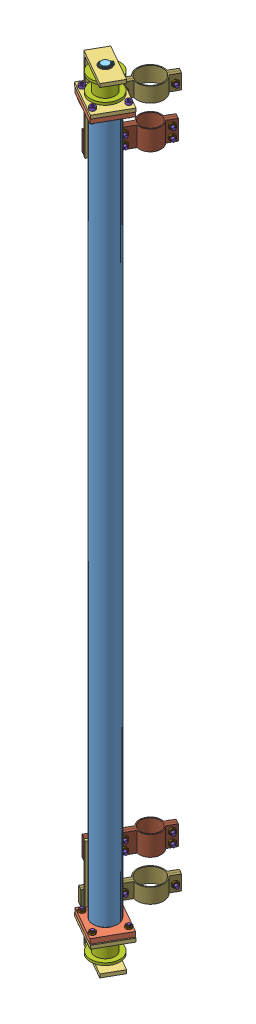
SolidWorks assembly 卷帘, configuration 默认. Lengths in mm.
Overall size (66.16 789.6 98.69).
107 component instances, 12 part files, 60 mates.
Components (placement in the parent):
- 平面涡卷弹簧内接侧-1: 平面涡卷弹簧内接侧 [默认] at (19.2815 -303.5885 0) size (25 712 25)
- 平面涡卷弹簧外接侧-1: 平面涡卷弹簧外接侧 [默认] at (23.7829 -661.5885 16.3627) x (0.49422 0 -0.869337) z (0.869337 0 0.49422) size (34 25 40)
- 平面涡卷弹簧外接侧-3: 平面涡卷弹簧外接侧 [默认] at (35.6442 54.4115 -4.5014) x (-0.49422 0 0.869337) z (0.869337 0 0.49422) size (34 25 40)
- 卷帘滑轮-安装-1: 卷帘滑轮-安装 [默认] at (13.2947 -733.0182 10.0249) x (0 1 0) z (-0.869337 0 -0.49422) size (94.8 34 43)
  - 卷帘安装架-1: 卷帘安装架 [默认] at (119.4297 11.8196 18.5) size (93 34 43)
  - deep groove ball bearings gb-1: deep groove ball bearings gb [Rolling bearings 617-8 GB 276-94] at (37.6797 11.6738 0) size (2.5 12 12)
  - deep groove ball bearings gb-2: deep groove ball bearings gb [Rolling bearings 617-8 GB 276-94] at (65.1797 11.6738 0) size (2.5 12 12)
  - 滑轮轴-1: 滑轮轴 [默认] at (51.4297 11.6738 0) x (0 0 1) z (-1 0 0) size (9.5 9.5 33.6)
  - circlips for shaft--type a small gb-2: circlips for shaft--type a small gb [GB_CONNECTING_PIECE_RING_RRA 8] at (66.4297 12.0038 0) x (0 0 1) z (-1 0 0) size (9.38 11.87 0.8)
  - circlips for shaft--type a small gb-3: circlips for shaft--type a small gb [GB_CONNECTING_PIECE_RING_RRA 8] at (36.4297 12.0038 0) x (0 0 -1) z (1 0 0) size (9.38 11.87 0.8)
  - 滑轮 - 卷帘-1: 滑轮 - 卷帘 [默认] at (41.4297 11.6738 0) x (0 -1 0) z (0 0 1) size (30 20 30)
- hexagon socket head cap screws gb-2: hexagon socket head cap screws gb [GB_FASTENER_SCREWS_HSHCS M3X12-N] at (38.3415 -673.0885 -4.6934) x (0 1 0) z (0 0 1) size (15 5.5 5.5)
- hexagon socket head cap screws gb-3: hexagon socket head cap screws gb [GB_FASTENER_SCREWS_HSHCS M3X12-N] at (13.5654 -673.0885 -18.7787) x (0 1 0) z (0 0 1) size (15 5.5 5.5)
- hexagon socket head cap screws gb-4: hexagon socket head cap screws gb [GB_FASTENER_SCREWS_HSHCS M3X12-N] at (0.2215 -673.0885 4.6934) x (0 1 0) z (0 0 1) size (15 5.5 5.5)
- hexagon socket head cap screws gb-5: hexagon socket head cap screws gb [GB_FASTENER_SCREWS_HSHCS M3X12-N] at (24.9976 -673.0885 18.7787) x (0 1 0) z (0 0 1) size (15 5.5 5.5)
- hex nuts, style 1-grades ab gb-2: hex nuts, style 1-grades ab gb [GB_FASTENER_NUT_SNAB1 M3-N] at (24.9976 -659.1885 18.7787) x (1 0 0) z (0 1 0) size (6.35 5.5 2.4)
- hex nuts, style 1-grades ab gb-3: hex nuts, style 1-grades ab gb [GB_FASTENER_NUT_SNAB1 M3-N] at (0.2215 -659.1885 4.6934) x (1 0 0) z (0 1 0) size (6.35 5.5 2.4)
- hex nuts, style 1-grades ab gb-4: hex nuts, style 1-grades ab gb [GB_FASTENER_NUT_SNAB1 M3-N] at (13.5654 -659.1885 -18.7787) x (1 0 0) z (0 1 0) size (6.35 5.5 2.4)
- hex nuts, style 1-grades ab gb-5: hex nuts, style 1-grades ab gb [GB_FASTENER_NUT_SNAB1 M3-N] at (38.3415 -659.1885 -4.6934) x (1 0 0) z (0 1 0) size (6.35 5.5 2.4)
- plain washers-n series-grade a gb-2: plain washers-n series-grade a gb [GB_FASTENER_WASHER_PWNA 3] at (-2.8064 -655.5885 -18.3081) x (-0.49422 0 0.869337) z (-0.869337 0 -0.49422) size (7 7 0.5)
- plain washers-n series-grade a gb-3: plain washers-n series-grade a gb [GB_FASTENER_WASHER_PWNA 3] at (-7.7485 -655.5885 -9.6148) x (-0.49422 0 0.869337) z (-0.869337 0 -0.49422) size (7 7 0.5)
- plain washers-n series-grade a gb-4: plain washers-n series-grade a gb [GB_FASTENER_WASHER_PWNA 3] at (-5.2773 -618.5885 -13.9617) x (-0.49422 0 0.869337) z (-0.869337 0 -0.49422) size (7 7 0.5)
- plain washers-n series-grade a gb-5: plain washers-n series-grade a gb [GB_FASTENER_WASHER_PWNA 3] at (-5.2773 -608.5885 -13.9617) x (-0.49422 0 0.869337) z (-0.869337 0 -0.49422) size (7 7 0.5)
- hexagon socket head cap screws gb-19: hexagon socket head cap screws gb [GB_FASTENER_SCREWS_HSHCS M3X16-N] at (-5.4144 -655.5885 -19.7908) x (0.869337 0 0.49422) z (-0.49422 0 0.869337) size (19 5.5 5.5)
- hexagon socket head cap screws gb-20: hexagon socket head cap screws gb [GB_FASTENER_SCREWS_HSHCS M3X16-N] at (-10.3566 -655.5885 -11.0974) x (0.869337 0 0.49422) z (-0.49422 0 0.869337) size (19 5.5 5.5)
- hexagon socket head cap screws gb-21: hexagon socket head cap screws gb [GB_FASTENER_SCREWS_HSHCS M3X16-N] at (-7.8853 -618.5885 -15.4444) x (0.869337 0 0.49422) z (-0.49422 0 0.869337) size (19 5.5 5.5)
- hexagon socket head cap screws gb-22: hexagon socket head cap screws gb [GB_FASTENER_SCREWS_HSHCS M3X16-N] at (-7.8853 -608.5885 -15.4444) x (0.869337 0 0.49422) z (-0.49422 0 0.869337) size (19 5.5 5.5)
- hex nuts, style 1-grades ab gb-19: hex nuts, style 1-grades ab gb [GB_FASTENER_NUT_SNAB1 M3-N] at (2.5966 -655.5885 -3.7335) x (0.49422 0 -0.869337) z (0.869337 0 0.49422) size (6.35 5.5 2.4)
- hex nuts, style 1-grades ab gb-20: hex nuts, style 1-grades ab gb [GB_FASTENER_NUT_SNAB1 M3-N] at (7.5388 -655.5885 -12.4269) x (0.49422 0 -0.869337) z (0.869337 0 0.49422) size (6.35 5.5 2.4)
- hex nuts, style 1-grades ab gb-21: hex nuts, style 1-grades ab gb [GB_FASTENER_NUT_SNAB1 M3-N] at (5.0678 -618.5885 -8.0805) x (0.49422 0 -0.869337) z (0.869337 0 0.49422) size (6.35 5.5 2.4)
- hex nuts, style 1-grades ab gb-22: hex nuts, style 1-grades ab gb [GB_FASTENER_NUT_SNAB1 M3-N] at (5.0678 -608.5885 -8.0805) x (0.49422 0 -0.869337) z (0.869337 0 0.49422) size (6.35 5.5 2.4)
- 卷帘滑轮-安装-4: 卷帘滑轮-安装 [默认] at (24.8336 125.8412 -10.272) x (0 -1 0) z (-0.869337 0 -0.49422) size (94.8 34 43)
  - 卷帘安装架-1: 卷帘安装架 [默认] at (119.4297 11.8196 18.5) size (93 34 43)
  - deep groove ball bearings gb-1: deep groove ball bearings gb [Rolling bearings 617-8 GB 276-94] at (37.6797 11.6738 0) size (2.5 12 12)
  - deep groove ball bearings gb-2: deep groove ball bearings gb [Rolling bearings 617-8 GB 276-94] at (65.1797 11.6738 0) size (2.5 12 12)
  - 滑轮轴-1: 滑轮轴 [默认] at (51.4297 11.6738 0) x (0 0 1) z (-1 0 0) size (9.5 9.5 33.6)
  - circlips for shaft--type a small gb-2: circlips for shaft--type a small gb [GB_CONNECTING_PIECE_RING_RRA 8] at (66.4297 12.0038 0) x (0 0 1) z (-1 0 0) size (9.38 11.87 0.8)
  - circlips for shaft--type a small gb-3: circlips for shaft--type a small gb [GB_CONNECTING_PIECE_RING_RRA 8] at (36.4297 12.0038 0) x (0 0 -1) z (1 0 0) size (9.38 11.87 0.8)
  - 滑轮 - 卷帘-1: 滑轮 - 卷帘 [默认] at (41.4297 11.6738 0) x (0 -1 0) z (0 0 1) size (30 20 30)
- hexagon socket head cap screws gb-14: hexagon socket head cap screws gb [GB_FASTENER_SCREWS_HSHCS M3X12-N] at (38.3415 65.9115 -4.6934) x (0 -1 0) z (0 0 -1) size (15 5.5 5.5)
- hexagon socket head cap screws gb-15: hexagon socket head cap screws gb [GB_FASTENER_SCREWS_HSHCS M3X12-N] at (13.5654 65.9115 -18.7787) x (0 -1 0) z (0 0 -1) size (15 5.5 5.5)
- hexagon socket head cap screws gb-16: hexagon socket head cap screws gb [GB_FASTENER_SCREWS_HSHCS M3X12-N] at (0.2215 65.9115 4.6934) x (0 -1 0) z (0 0 -1) size (15 5.5 5.5)
- hexagon socket head cap screws gb-17: hexagon socket head cap screws gb [GB_FASTENER_SCREWS_HSHCS M3X12-N] at (24.9976 65.9115 18.7787) x (0 -1 0) z (0 0 -1) size (15 5.5 5.5)
- hex nuts, style 1-grades ab gb-14: hex nuts, style 1-grades ab gb [GB_FASTENER_NUT_SNAB1 M3-N] at (24.9976 54.4115 18.7787) x (1 0 0) z (0 1 0) size (6.35 5.5 2.4)
- hex nuts, style 1-grades ab gb-15: hex nuts, style 1-grades ab gb [GB_FASTENER_NUT_SNAB1 M3-N] at (0.2215 54.4115 4.6934) x (1 0 0) z (0 1 0) size (6.35 5.5 2.4)
- hex nuts, style 1-grades ab gb-16: hex nuts, style 1-grades ab gb [GB_FASTENER_NUT_SNAB1 M3-N] at (13.5654 54.4115 -18.7787) x (1 0 0) z (0 1 0) size (6.35 5.5 2.4)
- hex nuts, style 1-grades ab gb-17: hex nuts, style 1-grades ab gb [GB_FASTENER_NUT_SNAB1 M3-N] at (38.3415 54.4115 -4.6934) x (1 0 0) z (0 1 0) size (6.35 5.5 2.4)
- 小管夹具-1: 小管夹具 [默认] at (50.6589 6.4115 7.2587) x (-0.869337 0 -0.49422) z (0 -1 0) size (22 70 20)
  - 夹具-1: 夹具 [默认] at (55.615 31.0944 -10) size (11 70 20)
  - 夹具-2: 夹具 [默认] at (55.615 31.0944 10) x (-1 0 0) z (0 0 -1) size (11 70 20)
  - plain washers-n series-grade a gb-2: plain washers-n series-grade a gb [GB_FASTENER_WASHER_PWNA 3] at (59.115 46.3859 5) x (0 0 -1) z (1 0 0) size (7 7 0.5)
  - plain washers-n series-grade a gb-3: plain washers-n series-grade a gb [GB_FASTENER_WASHER_PWNA 3] at (59.115 46.3859 -5) x (0 0 -1) z (1 0 0) size (7 7 0.5)
  - plain washers-n series-grade a gb-4: plain washers-n series-grade a gb [GB_FASTENER_WASHER_PWNA 3] at (59.115 10.8029 -5) x (0 0 -1) z (1 0 0) size (7 7 0.5)
  - plain washers-n series-grade a gb-5: plain washers-n series-grade a gb [GB_FASTENER_WASHER_PWNA 3] at (59.115 10.8029 5) x (0 0 -1) z (1 0 0) size (7 7 0.5)
  - hexagon socket head cap screws gb-2: hexagon socket head cap screws gb [GB_FASTENER_SCREWS_HSHCS M3X12-N] at (62.115 10.8029 -5) x (-1 0 0) z (0 0.924225 0.381849) size (15 5.5 5.5)
  - hexagon socket head cap screws gb-3: hexagon socket head cap screws gb [GB_FASTENER_SCREWS_HSHCS M3X12-N] at (62.115 10.8029 5) x (-1 0 0) z (0 0.924225 0.381849) size (15 5.5 5.5)
  - hexagon socket head cap screws gb-4: hexagon socket head cap screws gb [GB_FASTENER_SCREWS_HSHCS M3X12-N] at (62.115 46.3859 -5) x (-1 0 0) z (0 0.924225 0.381849) size (15 5.5 5.5)
  - hexagon socket head cap screws gb-5: hexagon socket head cap screws gb [GB_FASTENER_SCREWS_HSHCS M3X12-N] at (62.115 46.3859 5) x (-1 0 0) z (0 0.924225 0.381849) size (15 5.5 5.5)
  - hex nuts, style 1-grades ab gb-2: hex nuts, style 1-grades ab gb [GB_FASTENER_NUT_SNAB1 M3-N] at (50.215 10.8029 -5) x (0 0 1) z (-1 0 0) size (6.35 5.5 2.4)
  - hex nuts, style 1-grades ab gb-3: hex nuts, style 1-grades ab gb [GB_FASTENER_NUT_SNAB1 M3-N] at (50.215 10.8029 5) x (0 0 1) z (-1 0 0) size (6.35 5.5 2.4)
  - hex nuts, style 1-grades ab gb-4: hex nuts, style 1-grades ab gb [GB_FASTENER_NUT_SNAB1 M3-N] at (50.215 46.3859 -5) x (0 0 1) z (-1 0 0) size (6.35 5.5 2.4)
  - hex nuts, style 1-grades ab gb-5: hex nuts, style 1-grades ab gb [GB_FASTENER_NUT_SNAB1 M3-N] at (50.215 46.3859 5) x (0 0 1) z (-1 0 0) size (6.35 5.5 2.4)
- 小管夹具-2: 小管夹具 [默认] at (50.6589 -613.5885 7.2587) x (-0.869337 0 -0.49422) z (0 -1 0) size (22 70 20)
  - 夹具-1: 夹具 [默认] at (55.615 31.0944 -10) size (11 70 20)
  - 夹具-2: 夹具 [默认] at (55.615 31.0944 10) x (-1 0 0) z (0 0 -1) size (11 70 20)
  - plain washers-n series-grade a gb-2: plain washers-n series-grade a gb [GB_FASTENER_WASHER_PWNA 3] at (59.115 46.3859 5) x (0 0 -1) z (1 0 0) size (7 7 0.5)
  - plain washers-n series-grade a gb-3: plain washers-n series-grade a gb [GB_FASTENER_WASHER_PWNA 3] at (59.115 46.3859 -5) x (0 0 -1) z (1 0 0) size (7 7 0.5)
  - plain washers-n series-grade a gb-4: plain washers-n series-grade a gb [GB_FASTENER_WASHER_PWNA 3] at (59.115 10.8029 -5) x (0 0 -1) z (1 0 0) size (7 7 0.5)
  - plain washers-n series-grade a gb-5: plain washers-n series-grade a gb [GB_FASTENER_WASHER_PWNA 3] at (59.115 10.8029 5) x (0 0 -1) z (1 0 0) size (7 7 0.5)
  - hexagon socket head cap screws gb-2: hexagon socket head cap screws gb [GB_FASTENER_SCREWS_HSHCS M3X12-N] at (62.115 10.8029 -5) x (-1 0 0) z (0 0.924225 0.381849) size (15 5.5 5.5)
  - hexagon socket head cap screws gb-3: hexagon socket head cap screws gb [GB_FASTENER_SCREWS_HSHCS M3X12-N] at (62.115 10.8029 5) x (-1 0 0) z (0 0.924225 0.381849) size (15 5.5 5.5)
  - hexagon socket head cap screws gb-4: hexagon socket head cap screws gb [GB_FASTENER_SCREWS_HSHCS M3X12-N] at (62.115 46.3859 -5) x (-1 0 0) z (0 0.924225 0.381849) size (15 5.5 5.5)
  - hexagon socket head cap screws gb-5: hexagon socket head cap screws gb [GB_FASTENER_SCREWS_HSHCS M3X12-N] at (62.115 46.3859 5) x (-1 0 0) z (0 0.924225 0.381849) size (15 5.5 5.5)
  - hex nuts, style 1-grades ab gb-2: hex nuts, style 1-grades ab gb [GB_FASTENER_NUT_SNAB1 M3-N] at (50.215 10.8029 -5) x (0 0 1) z (-1 0 0) size (6.35 5.5 2.4)
  - hex nuts, style 1-grades ab gb-3: hex nuts, style 1-grades ab gb [GB_FASTENER_NUT_SNAB1 M3-N] at (50.215 10.8029 5) x (0 0 1) z (-1 0 0) size (6.35 5.5 2.4)
  - hex nuts, style 1-grades ab gb-4: hex nuts, style 1-grades ab gb [GB_FASTENER_NUT_SNAB1 M3-N] at (50.215 46.3859 -5) x (0 0 1) z (-1 0 0) size (6.35 5.5 2.4)
  - hex nuts, style 1-grades ab gb-5: hex nuts, style 1-grades ab gb [GB_FASTENER_NUT_SNAB1 M3-N] at (50.215 46.3859 5) x (0 0 1) z (-1 0 0) size (6.35 5.5 2.4)
- 大管夹具-1: 大管夹具 [默认] at (37.4366 48.4115 -23.0824) x (-0.869337 0 -0.49422) z (0 -1 0) size (27 74.91 15)
  - 窄夹具-1: 窄夹具 [默认] at (29.1251 11.2528 -7.5) size (13.5 74.91 15)
  - 窄夹具-2: 窄夹具 [默认] at (29.1251 11.2528 7.5) x (-1 0 0) z (0 0 -1) size (13.5 74.91 15)
  - plain washers-n series-grade a gb-2: plain washers-n series-grade a gb [GB_FASTENER_WASHER_PWNA 3] at (32.6251 28.9495 0) x (0 0 -1) z (1 0 0) size (7 7 0.5)
  - plain washers-n series-grade a gb-3: plain washers-n series-grade a gb [GB_FASTENER_WASHER_PWNA 3] at (32.6251 -9.0387 0) x (0 0 -1) z (1 0 0) size (7 7 0.5)
  - hexagon socket head cap screws gb-2: hexagon socket head cap screws gb [GB_FASTENER_SCREWS_HSHCS M3X12-N] at (35.6251 -9.0387 0) x (-1 0 0) z (0 0.924225 0.381849) size (15 5.5 5.5)
  - hexagon socket head cap screws gb-3: hexagon socket head cap screws gb [GB_FASTENER_SCREWS_HSHCS M3X12-N] at (35.6251 28.9495 0) x (-1 0 0) z (0 0.924225 0.381849) size (15 5.5 5.5)
  - hex nuts, style 1-grades ab gb-2: hex nuts, style 1-grades ab gb [GB_FASTENER_NUT_SNAB1 M3-N] at (23.7251 28.9495 0) x (0 0 1) z (-1 0 0) size (6.35 5.5 2.4)
  - hex nuts, style 1-grades ab gb-3: hex nuts, style 1-grades ab gb [GB_FASTENER_NUT_SNAB1 M3-N] at (23.7251 -9.0387 0) x (0 0 1) z (-1 0 0) size (6.35 5.5 2.4)
- 大管夹具-2: 大管夹具 [默认] at (37.4363 -655.5885 -23.0819) x (-0.869337 0 -0.49422) z (0 -1 0) size (27 74.91 15)
  - 窄夹具-1: 窄夹具 [默认] at (29.1251 11.2528 -7.5) size (13.5 74.91 15)
  - 窄夹具-2: 窄夹具 [默认] at (29.1251 11.2528 7.5) x (-1 0 0) z (0 0 -1) size (13.5 74.91 15)
  - plain washers-n series-grade a gb-2: plain washers-n series-grade a gb [GB_FASTENER_WASHER_PWNA 3] at (32.6251 28.9495 0) x (0 0 -1) z (1 0 0) size (7 7 0.5)
  - plain washers-n series-grade a gb-3: plain washers-n series-grade a gb [GB_FASTENER_WASHER_PWNA 3] at (32.6251 -9.0387 0) x (0 0 -1) z (1 0 0) size (7 7 0.5)
  - hexagon socket head cap screws gb-2: hexagon socket head cap screws gb [GB_FASTENER_SCREWS_HSHCS M3X12-N] at (35.6251 -9.0387 0) x (-1 0 0) z (0 0.924225 0.381849) size (15 5.5 5.5)
  - hexagon socket head cap screws gb-3: hexagon socket head cap screws gb [GB_FASTENER_SCREWS_HSHCS M3X12-N] at (35.6251 28.9495 0) x (-1 0 0) z (0 0.924225 0.381849) size (15 5.5 5.5)
  - hex nuts, style 1-grades ab gb-2: hex nuts, style 1-grades ab gb [GB_FASTENER_NUT_SNAB1 M3-N] at (23.7251 28.9495 0) x (0 0 1) z (-1 0 0) size (6.35 5.5 2.4)
  - hex nuts, style 1-grades ab gb-3: hex nuts, style 1-grades ab gb [GB_FASTENER_NUT_SNAB1 M3-N] at (23.7251 -9.0387 0) x (0 0 1) z (-1 0 0) size (6.35 5.5 2.4)
- hex nuts, style 1-grades ab gb-23: hex nuts, style 1-grades ab gb [GB_FASTENER_NUT_SNAB1 M3-N] at (2.9814 1.4115 -9.2666) x (0.49422 0 -0.869337) z (-0.869337 0 -0.49422) size (6.35 5.5 2.4)
- hex nuts, style 1-grades ab gb-24: hex nuts, style 1-grades ab gb [GB_FASTENER_NUT_SNAB1 M3-N] at (2.9814 11.4115 -9.2666) x (0.49422 0 -0.869337) z (-0.869337 0 -0.49422) size (6.35 5.5 2.4)
- hex nuts, style 1-grades ab gb-25: hex nuts, style 1-grades ab gb [GB_FASTENER_NUT_SNAB1 M3-N] at (5.4524 48.4115 -13.613) x (0.49422 0 -0.869337) z (-0.869337 0 -0.49422) size (6.35 5.5 2.4)
- hex nuts, style 1-grades ab gb-26: hex nuts, style 1-grades ab gb [GB_FASTENER_NUT_SNAB1 M3-N] at (0.5102 48.4115 -4.9197) x (0.49422 0 -0.869337) z (-0.869337 0 -0.49422) size (6.35 5.5 2.4)
- hexagon socket head cap screws gb-23: hexagon socket head cap screws gb [GB_FASTENER_SCREWS_HSHCS M3X16-N] at (-7.8853 1.4115 -15.4444) x (0.869337 0 0.49422) z (0.49422 0 -0.869337) size (19 5.5 5.5)
- hexagon socket head cap screws gb-24: hexagon socket head cap screws gb [GB_FASTENER_SCREWS_HSHCS M3X16-N] at (-7.8853 11.4115 -15.4444) x (0.869337 0 0.49422) z (0.49422 0 -0.869337) size (19 5.5 5.5)
- hexagon socket head cap screws gb-25: hexagon socket head cap screws gb [GB_FASTENER_SCREWS_HSHCS M3X16-N] at (-10.3566 48.4115 -11.0974) x (0.869337 0 0.49422) z (0.49422 0 -0.869337) size (19 5.5 5.5)
- hexagon socket head cap screws gb-26: hexagon socket head cap screws gb [GB_FASTENER_SCREWS_HSHCS M3X16-N] at (-5.4144 48.4115 -19.7908) x (0.869337 0 0.49422) z (0.49422 0 -0.869337) size (19 5.5 5.5)
- plain washers-n series-grade a gb-6: plain washers-n series-grade a gb [GB_FASTENER_WASHER_PWNA 3] at (-4.8426 1.4115 -13.7146) x (-0.49422 0 0.869337) z (0.869337 0 0.49422) size (7 7 0.5)
- plain washers-n series-grade a gb-7: plain washers-n series-grade a gb [GB_FASTENER_WASHER_PWNA 3] at (-4.8426 11.4115 -13.7146) x (-0.49422 0 0.869337) z (0.869337 0 0.49422) size (7 7 0.5)
- plain washers-n series-grade a gb-8: plain washers-n series-grade a gb [GB_FASTENER_WASHER_PWNA 3] at (-7.3139 48.4115 -9.3677) x (-0.49422 0 0.869337) z (0.869337 0 0.49422) size (7 7 0.5)
- plain washers-n series-grade a gb-9: plain washers-n series-grade a gb [GB_FASTENER_WASHER_PWNA 3] at (-2.3717 48.4115 -18.061) x (-0.49422 0 0.869337) z (0.869337 0 0.49422) size (7 7 0.5)
Mates (geometry in assembly coordinates):
- 同心1: concentric aligned: cylinder of 平面涡卷弹簧内接侧-1 through (19.2815 -639.5885 0) axis (0 -1 0) radius 12; cylinder of 平面涡卷弹簧外接侧-1 through (19.2815 -641.5885 0) axis (0 -1 0) radius 10
- 距离1: distance = 2 mm anti-aligned: plane of 平面涡卷弹簧外接侧-1 through (23.7829 -641.5885 16.3627) normal (0 1 0); plane of 平面涡卷弹簧内接侧-1 through (19.2815 -639.5885 0) normal (0 -1 0)
- 同心3: concentric aligned: cylinder of 平面涡卷弹簧内接侧-1 through (19.2815 32.4115 0) axis (0 1 0) radius 10; cylinder of 平面涡卷弹簧外接侧-3 through (19.2815 34.4115 0) axis (0 1 0) radius 10
- 距离3: distance = 2 mm anti-aligned: plane of 平面涡卷弹簧外接侧-3 through (35.6442 34.4115 -4.5014) normal (0 -1 0); plane of 平面涡卷弹簧内接侧-1 through (19.2815 32.4115 0) normal (0 1 0)
- 重合3: coincident aligned: plane of 平面涡卷弹簧外接侧-1 through (30.7376 -666.5885 20.3164) normal (0.869337 0 0.49422); plane of 平面涡卷弹簧外接侧-3 through (42.5988 59.4115 -0.5477) normal (0.869337 0 0.49422)
- 重合6: coincident anti-aligned: plane of 平面涡卷弹簧外接侧-1 through (23.7829 -666.5885 16.3627) normal (0 -1 0); plane of 卷帘滑轮-安装-1/卷帘安装架-1 through (0.4454 -666.5885 -10.876) normal (0 1 0)
- 同心6: concentric anti-aligned: cylinder of 平面涡卷弹簧外接侧-1 through (0.2215 -671.5885 4.6934) axis (0 1 0) radius 1.5; cylinder of 卷帘滑轮-安装-1/卷帘安装架-1 through (0.2215 -656.5885 4.6934) axis (0 -1 0) radius 1.5
- 同心7: concentric anti-aligned: cylinder of 平面涡卷弹簧外接侧-1 through (24.9976 -671.5885 18.7787) axis (0 1 0) radius 1.5; cylinder of 卷帘滑轮-安装-1/卷帘安装架-1 through (24.9976 -656.5885 18.7787) axis (0 -1 0) radius 1.5
- 同心8: concentric aligned: cylinder of 卷帘滑轮-安装-1/卷帘安装架-1 through (38.3415 -656.5885 -4.6934) axis (0 -1 0) radius 1.5; cylinder of hexagon socket head cap screws gb-2 through (38.3415 -658.0885 -4.6934) axis (0 -1 0) radius 1.5
- 重合7: coincident anti-aligned: plane of 卷帘滑轮-安装-1/卷帘安装架-1 through (0.4454 -670.0885 -10.876) normal (0 -1 0); plane of hexagon socket head cap screws gb-2 through (38.3415 -670.0885 -4.6934) normal (0 1 0)
- 同心9: concentric aligned: cylinder of 卷帘滑轮-安装-1/卷帘安装架-1 through (13.5654 -656.5885 -18.7787) axis (0 -1 0) radius 1.5; cylinder of hexagon socket head cap screws gb-3 through (13.5654 -658.0885 -18.7787) axis (0 -1 0) radius 1.5
- 重合8: coincident anti-aligned: plane of 卷帘滑轮-安装-1/卷帘安装架-1 through (0.4454 -670.0885 -10.876) normal (0 -1 0); plane of hexagon socket head cap screws gb-3 through (13.5654 -670.0885 -18.7787) normal (0 1 0)
- 同心10: concentric aligned: cylinder of 卷帘滑轮-安装-1/卷帘安装架-1 through (0.2215 -656.5885 4.6934) axis (0 -1 0) radius 1.5; cylinder of hexagon socket head cap screws gb-4 through (0.2215 -658.0885 4.6934) axis (0 -1 0) radius 1.5
- 重合9: coincident anti-aligned: plane of 卷帘滑轮-安装-1/卷帘安装架-1 through (0.4454 -670.0885 -10.876) normal (0 -1 0); plane of hexagon socket head cap screws gb-4 through (0.2215 -670.0885 4.6934) normal (0 1 0)
- 同心11: concentric aligned: cylinder of 卷帘滑轮-安装-1/卷帘安装架-1 through (24.9976 -656.5885 18.7787) axis (0 -1 0) radius 1.5; cylinder of hexagon socket head cap screws gb-5 through (24.9976 -658.0885 18.7787) axis (0 -1 0) radius 1.5
- 重合10: coincident anti-aligned: plane of 卷帘滑轮-安装-1/卷帘安装架-1 through (0.4454 -670.0885 -10.876) normal (0 -1 0); plane of hexagon socket head cap screws gb-5 through (24.9976 -670.0885 18.7787) normal (0 1 0)
- 同心12: concentric anti-aligned: cylinder of hexagon socket head cap screws gb-5 through (24.9976 -658.0885 18.7787) axis (0 -1 0) radius 1.5; cone of hex nuts, style 1-grades ab gb-2 through (24.9976 -661.5885 18.7787) axis (0 1 0)
- 重合11: coincident anti-aligned: plane of 平面涡卷弹簧外接侧-1 through (23.7829 -661.5885 16.3627) normal (0 1 0); plane of hex nuts, style 1-grades ab gb-2 through (24.9976 -661.5885 24.2787) normal (0 -1 0)
- 同心13: concentric anti-aligned: cylinder of hexagon socket head cap screws gb-4 through (0.2215 -658.0885 4.6934) axis (0 -1 0) radius 1.5; cone of hex nuts, style 1-grades ab gb-3 through (0.2215 -661.5885 4.6934) axis (0 1 0)
- 重合12: coincident anti-aligned: plane of 平面涡卷弹簧外接侧-1 through (23.7829 -661.5885 16.3627) normal (0 1 0); plane of hex nuts, style 1-grades ab gb-3 through (0.2215 -661.5885 10.1934) normal (0 -1 0)
- 同心14: concentric anti-aligned: cylinder of hexagon socket head cap screws gb-3 through (13.5654 -658.0885 -18.7787) axis (0 -1 0) radius 1.5; cone of hex nuts, style 1-grades ab gb-4 through (13.5654 -661.5885 -18.7787) axis (0 1 0)
- 重合13: coincident anti-aligned: plane of 平面涡卷弹簧外接侧-1 through (23.7829 -661.5885 16.3627) normal (0 1 0); plane of hex nuts, style 1-grades ab gb-4 through (13.5654 -661.5885 -13.2787) normal (0 -1 0)
- 同心15: concentric anti-aligned: cylinder of hexagon socket head cap screws gb-2 through (38.3415 -658.0885 -4.6934) axis (0 -1 0) radius 1.5; cone of hex nuts, style 1-grades ab gb-5 through (38.3415 -661.5885 -4.6934) axis (0 1 0)
- 重合14: coincident anti-aligned: plane of 平面涡卷弹簧外接侧-1 through (23.7829 -661.5885 16.3627) normal (0 1 0); plane of hex nuts, style 1-grades ab gb-5 through (38.3415 -661.5885 0.8066) normal (0 -1 0)
- 同心19: concentric anti-aligned: cylinder of 卷帘滑轮-安装-1/卷帘安装架-1 through (0.3734 -618.5885 -10.7493) axis (0.869337 0 0.49422) radius 1.5; cylinder of 小管夹具-2/夹具-2 through (12.5441 -618.5885 -3.8302) axis (-0.869337 0 -0.49422) radius 1.5
- 同心20: concentric anti-aligned: cylinder of 卷帘滑轮-安装-1/卷帘安装架-1 through (0.3734 -608.5885 -10.7493) axis (0.869337 0 0.49422) radius 1.5; cylinder of 小管夹具-2/夹具-2 through (12.5441 -608.5885 -3.8302) axis (-0.869337 0 -0.49422) radius 1.5
- 重合16: coincident anti-aligned: plane of 卷帘滑轮-安装-1/卷帘安装架-1 through (0.4454 -613.5885 -10.876) normal (-0.869337 0 -0.49422); plane of 小管夹具-2/夹具-1 through (20.2862 -623.5885 -45.7762) normal (0.869337 0 0.49422)
- 同心21: concentric anti-aligned: cylinder of 卷帘滑轮-安装-4/卷帘安装架-1 through (0.3734 1.4115 -10.7493) axis (0.869337 0 0.49422) radius 1.5; cylinder of 小管夹具-1/夹具-2 through (12.5441 1.4115 -3.8302) axis (-0.869337 0 -0.49422) radius 1.5
- 同心22: concentric anti-aligned: cylinder of 卷帘滑轮-安装-4/卷帘安装架-1 through (0.3734 11.4115 -10.7493) axis (0.869337 0 0.49422) radius 1.5; cylinder of 小管夹具-1/夹具-2 through (12.5441 11.4115 -3.8302) axis (-0.869337 0 -0.49422) radius 1.5
- 重合17: coincident anti-aligned: plane of 卷帘滑轮-安装-4/卷帘安装架-1 through (0.3014 6.4115 -10.6226) normal (-0.869337 0 -0.49422); plane of 小管夹具-1/夹具-1 through (20.2862 -3.5885 -45.7762) normal (0.869337 0 0.49422)
- 同心231: concentric aligned: cylinder of 卷帘滑轮-安装-4/卷帘安装架-1 through (7.1913 48.4115 -12.6251) axis (-0.869337 0 -0.49422) radius 1.5; cylinder of 大管夹具-1/窄夹具-2 through (15.0154 48.4115 -8.1771) axis (-0.869337 0 -0.49422) radius 1.5
- 同心241: concentric aligned: cylinder of 卷帘滑轮-安装-4/卷帘安装架-1 through (2.2491 48.4115 -3.9318) axis (-0.869337 0 -0.49422) radius 1.5; cylinder of 大管夹具-1/窄夹具-2 through (10.0732 48.4115 0.5162) axis (-0.869337 0 -0.49422) radius 1.5
- 重合181: coincident anti-aligned: plane of 卷帘滑轮-安装-4/卷帘安装架-1 through (0.3014 6.4115 -10.6226) normal (-0.869337 0 -0.49422); plane of 大管夹具-1/窄夹具-1 through (20.2864 40.9115 -45.7764) normal (0.869337 0 0.49422)
- 同心251: concentric aligned: cylinder of 卷帘滑轮-安装-1/卷帘安装架-1 through (7.191 -655.5885 -12.6246) axis (-0.869337 0 -0.49422) radius 1.5; cylinder of 大管夹具-2/窄夹具-2 through (15.0151 -655.5885 -8.1766) axis (-0.869337 0 -0.49422) radius 1.5
- 同心261: concentric aligned: cylinder of 卷帘滑轮-安装-1/卷帘安装架-1 through (2.2488 -655.5885 -3.9312) axis (-0.869337 0 -0.49422) radius 1.5; cylinder of 大管夹具-2/窄夹具-2 through (10.0729 -655.5885 0.5167) axis (-0.869337 0 -0.49422) radius 1.5
- 重合191: coincident anti-aligned: plane of 卷帘滑轮-安装-1/卷帘安装架-1 through (0.4454 -613.5885 -10.876) normal (-0.869337 0 -0.49422); plane of 大管夹具-2/窄夹具-1 through (20.2861 -663.0885 -45.7759) normal (0.869337 0 0.49422)
- 同心27: concentric aligned: cylinder of 大管夹具-2/窄夹具-2 through (15.0151 -655.5885 -8.1766) axis (-0.869337 0 -0.49422) radius 1.5; cylinder of plain washers-n series-grade a gb-2 through (-2.3717 -655.5885 -18.061) axis (-0.869337 0 -0.49422) radius 1.6
- 重合20: coincident anti-aligned: plane of 大管夹具-2/窄夹具-2 through (15.0701 -648.0885 -48.7412) normal (-0.869337 0 -0.49422); plane of plain washers-n series-grade a gb-2 through (-2.3717 -655.5885 -18.061) normal (0.869337 0 0.49422)
- 同心28: concentric aligned: cylinder of 大管夹具-2/窄夹具-2 through (10.0729 -655.5885 0.5167) axis (-0.869337 0 -0.49422) radius 1.5; cylinder of plain washers-n series-grade a gb-3 through (-7.3139 -655.5885 -9.3677) axis (-0.869337 0 -0.49422) radius 1.6
- 重合21: coincident anti-aligned: plane of 大管夹具-2/窄夹具-2 through (15.0701 -648.0885 -48.7412) normal (-0.869337 0 -0.49422); plane of plain washers-n series-grade a gb-3 through (-7.3139 -655.5885 -9.3677) normal (0.869337 0 0.49422)
- 同心29: concentric aligned: cylinder of 小管夹具-2/夹具-2 through (12.5441 -618.5885 -3.8302) axis (-0.869337 0 -0.49422) radius 1.5; cylinder of plain washers-n series-grade a gb-4 through (-4.8426 -618.5885 -13.7146) axis (-0.869337 0 -0.49422) radius 1.6
- 重合22: coincident anti-aligned: plane of 小管夹具-2/夹具-2 through (15.0702 -603.5885 -48.7415) normal (-0.869337 0 -0.49422); plane of plain washers-n series-grade a gb-4 through (-4.8426 -618.5885 -13.7146) normal (0.869337 0 0.49422)
- 同心30: concentric aligned: cylinder of 小管夹具-2/夹具-2 through (12.5441 -608.5885 -3.8302) axis (-0.869337 0 -0.49422) radius 1.5; cylinder of plain washers-n series-grade a gb-5 through (-4.8426 -608.5885 -13.7146) axis (-0.869337 0 -0.49422) radius 1.6
- 重合23: coincident anti-aligned: plane of 小管夹具-2/夹具-2 through (15.0702 -603.5885 -48.7415) normal (-0.869337 0 -0.49422); plane of plain washers-n series-grade a gb-5 through (-4.8426 -608.5885 -13.7146) normal (0.869337 0 0.49422)
- 同心31: concentric aligned: cylinder of 大管夹具-2/窄夹具-2 through (15.0151 -655.5885 -8.1766) axis (-0.869337 0 -0.49422) radius 1.5; cylinder of hexagon socket head cap screws gb-19 through (11.103 -655.5885 -10.4006) axis (-0.869337 0 -0.49422) radius 1.5
- 重合24: coincident anti-aligned: plane of plain washers-n series-grade a gb-2 through (-2.8064 -655.5885 -18.3081) normal (-0.869337 0 -0.49422); plane of hexagon socket head cap screws gb-19 through (-2.8064 -655.5885 -18.3081) normal (0.869337 0 0.49422)
- 同心32: concentric aligned: cylinder of 大管夹具-2/窄夹具-2 through (10.0729 -655.5885 0.5167) axis (-0.869337 0 -0.49422) radius 1.5; cylinder of hexagon socket head cap screws gb-20 through (6.1608 -655.5885 -1.7072) axis (-0.869337 0 -0.49422) radius 1.5
- 重合25: coincident anti-aligned: plane of plain washers-n series-grade a gb-3 through (-7.7485 -655.5885 -9.6148) normal (-0.869337 0 -0.49422); plane of hexagon socket head cap screws gb-20 through (-7.7485 -655.5885 -9.6148) normal (0.869337 0 0.49422)
- 同心33: concentric aligned: cylinder of 小管夹具-2/夹具-2 through (12.5441 -618.5885 -3.8302) axis (-0.869337 0 -0.49422) radius 1.5; cylinder of hexagon socket head cap screws gb-21 through (8.6321 -618.5885 -6.0542) axis (-0.869337 0 -0.49422) radius 1.5
- 重合26: coincident anti-aligned: plane of plain washers-n series-grade a gb-4 through (-5.2773 -618.5885 -13.9617) normal (-0.869337 0 -0.49422); plane of hexagon socket head cap screws gb-21 through (-5.2773 -618.5885 -13.9617) normal (0.869337 0 0.49422)
- 同心34: concentric aligned: cylinder of 小管夹具-2/夹具-2 through (12.5441 -608.5885 -3.8302) axis (-0.869337 0 -0.49422) radius 1.5; cylinder of hexagon socket head cap screws gb-22 through (8.6321 -608.5885 -6.0542) axis (-0.869337 0 -0.49422) radius 1.5
- 重合27: coincident anti-aligned: plane of plain washers-n series-grade a gb-5 through (-5.2773 -608.5885 -13.9617) normal (-0.869337 0 -0.49422); plane of hexagon socket head cap screws gb-22 through (-5.2773 -608.5885 -13.9617) normal (0.869337 0 0.49422)
- 同心35: concentric anti-aligned: cylinder of hexagon socket head cap screws gb-20 through (6.1608 -655.5885 -1.7072) axis (-0.869337 0 -0.49422) radius 1.5; cone of hex nuts, style 1-grades ab gb-19 through (0.5102 -655.5885 -4.9197) axis (0.869337 0 0.49422)
- 重合28: coincident anti-aligned: plane of 卷帘滑轮-安装-1/卷帘安装架-1 through (3.0534 -613.5885 -9.3933) normal (0.869337 0 0.49422); plane of hex nuts, style 1-grades ab gb-19 through (0.5102 -661.0885 -4.9197) normal (-0.869337 0 -0.49422)
- 同心36: concentric anti-aligned: cylinder of hexagon socket head cap screws gb-19 through (11.103 -655.5885 -10.4006) axis (-0.869337 0 -0.49422) radius 1.5; cone of hex nuts, style 1-grades ab gb-20 through (5.4524 -655.5885 -13.613) axis (0.869337 0 0.49422)
- 重合29: coincident anti-aligned: plane of 卷帘滑轮-安装-1/卷帘安装架-1 through (3.0534 -613.5885 -9.3933) normal (0.869337 0 0.49422); plane of hex nuts, style 1-grades ab gb-20 through (5.4524 -661.0885 -13.613) normal (-0.869337 0 -0.49422)
- 同心37: concentric anti-aligned: cylinder of hexagon socket head cap screws gb-21 through (8.6321 -618.5885 -6.0542) axis (-0.869337 0 -0.49422) radius 1.5; cone of hex nuts, style 1-grades ab gb-21 through (2.9814 -618.5885 -9.2666) axis (0.869337 0 0.49422)
- 重合30: coincident anti-aligned: plane of 卷帘滑轮-安装-1/卷帘安装架-1 through (3.0534 -613.5885 -9.3933) normal (0.869337 0 0.49422); plane of hex nuts, style 1-grades ab gb-21 through (2.9814 -624.0885 -9.2666) normal (-0.869337 0 -0.49422)
- 同心38: concentric anti-aligned: cylinder of hexagon socket head cap screws gb-22 through (8.6321 -608.5885 -6.0542) axis (-0.869337 0 -0.49422) radius 1.5; cone of hex nuts, style 1-grades ab gb-22 through (2.9814 -608.5885 -9.2666) axis (0.869337 0 0.49422)
- 重合31: coincident anti-aligned: plane of 卷帘滑轮-安装-1/卷帘安装架-1 through (3.0534 -613.5885 -9.3933) normal (0.869337 0 0.49422); plane of hex nuts, style 1-grades ab gb-22 through (2.9814 -614.0885 -9.2666) normal (-0.869337 0 -0.49422)
